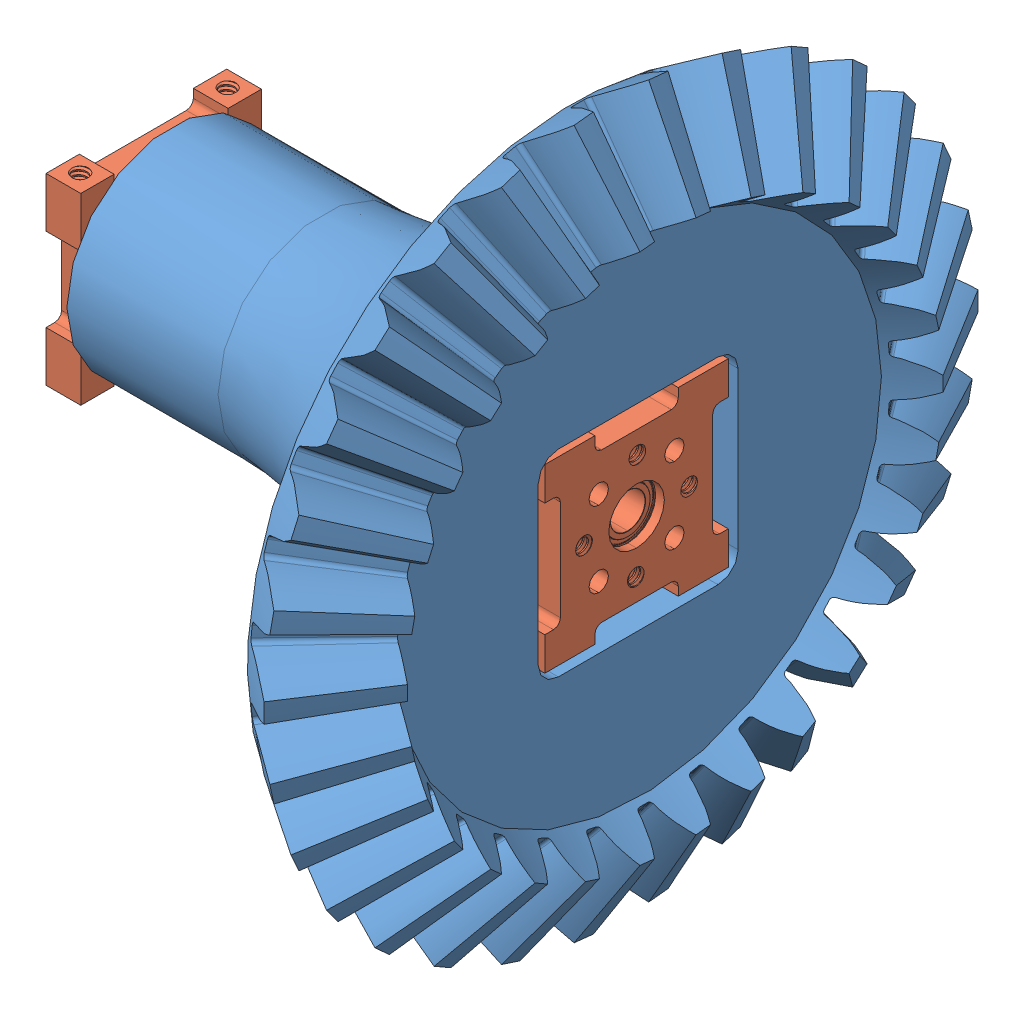
SolidWorks assembly ARMUS-REV2-400, configuration Défaut. Lengths in mm.
Overall size (99.55 130.43 130.79).
3 component instances, 2 part files, 8 mates.
Components (placement in the parent):
- ARMUS-REV2-401-1: ARMUS-REV2-401 [Default] at origin size (93.2 130.43 130.79)
- Bore Side Tapped Pillow Block 1.25-1: Bore Side Tapped Pillow Block 1.25 [Default] at (-58.9626 7.6184 28.3917) x (0 -1 0) z (0 0 -1) size (33.54 6.35 33.02)
- Bore Side Tapped Pillow Block 1.25-2: Bore Side Tapped Pillow Block 1.25 [Default] at (26.0822 -28.3917 7.6184) x (0 0 -1) z (0 1 0) size (33.54 6.35 33.02)
Mates (geometry in assembly coordinates):
- Concentric294: concentric anti-aligned: cylinder of ARMUS-REV2-401-1 through (128.2701 0 0) axis (-1 0 0) radius 6.35; cylinder of Bore Side Tapped Pillow Block 1.25-2 through (5.5295 0 0) axis (1 0 0) radius 3.175
- Concentric296: concentric anti-aligned: cylinder of ARMUS-REV2-401-1 through (5.5168 -6.9148 -6.9148) axis (1 0 0) radius 1.25; cylinder of Bore Side Tapped Pillow Block 1.25-2 through (5.5168 -6.9148 -6.9148) axis (-1 0 0) radius 1.778
- Concentric297: concentric anti-aligned: cylinder of ARMUS-REV2-401-1 through (5.5168 6.9148 -6.9148) axis (1 0 0) radius 1.25; cylinder of Bore Side Tapped Pillow Block 1.25-2 through (5.5168 6.9148 -6.9148) axis (-1 0 0) radius 1.778
- Coincident59: coincident anti-aligned: plane of ARMUS-REV2-401-1 through (5.5168 0 0) normal (1 0 0); plane of Bore Side Tapped Pillow Block 1.25-2 through (5.5168 0 0) normal (-1 0 0)
- Coincident60: coordinate: point of ARMUS-REV2-401-1
- Concentric299: concentric anti-aligned: cylinder of ARMUS-REV2-401-1 through (5.5168 -6.9148 -6.9148) axis (1 0 0) radius 1.25; cylinder of Bore Side Tapped Pillow Block 1.25-1 through (-79.5281 -6.9148 -6.9148) axis (-1 0 0) radius 1.778
- Coincident61: coincident anti-aligned: plane of ARMUS-REV2-401-1 through (-73.1781 -65.2174 -19.05) normal (-1 0 0); plane of Bore Side Tapped Pillow Block 1.25-1 through (-73.1781 0 0) normal (1 0 0)
- Concentric301: concentric anti-aligned: cylinder of ARMUS-REV2-401-1 through (5.5168 6.9148 6.9148) axis (1 0 0) radius 1.25; cylinder of Bore Side Tapped Pillow Block 1.25-1 through (-79.5281 6.9148 6.9148) axis (-1 0 0) radius 1.778
